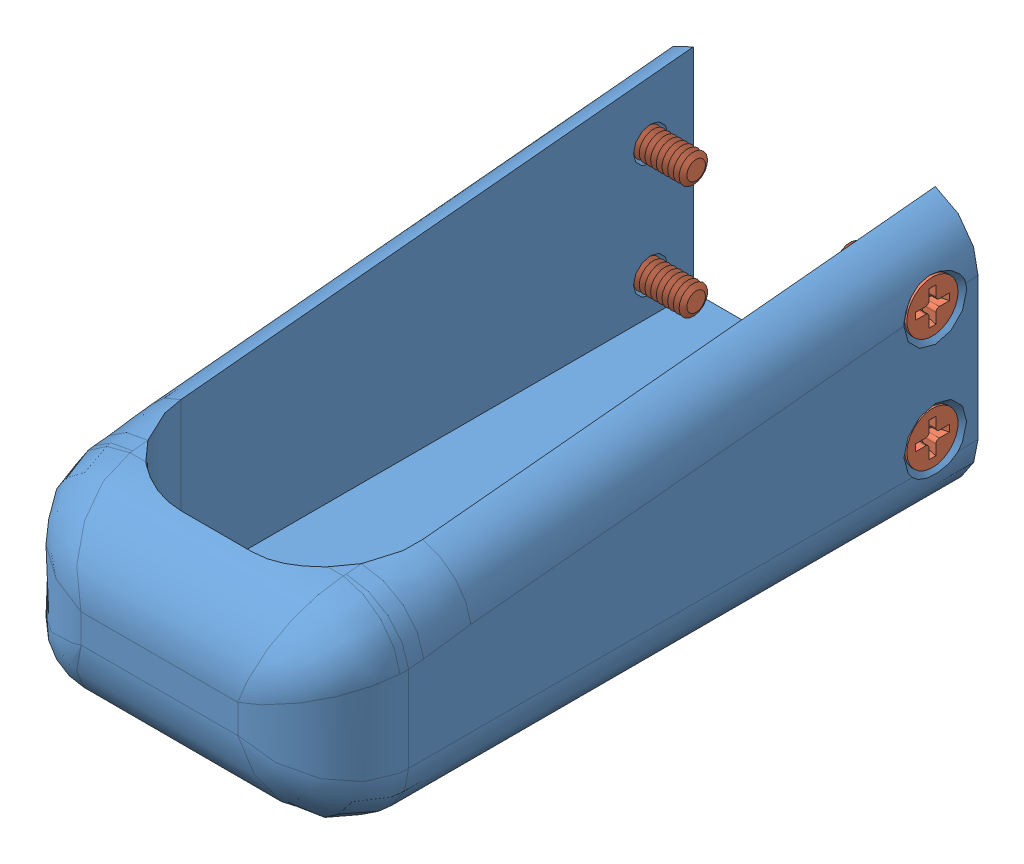
SolidWorks assembly B2586, configuration Default. Lengths in mm.
Overall size (23.31 17.9 46).
5 component instances, 2 part files, 9 mates.
Components (placement in the parent):
- B0926-1: B0926 [Default] at (0 0 -46) x (-1 0 0) z (0 1 0) size (23.31 46 17.9)
- B1090-1: B1090 [M2-.4x6] at (10.3 13.5 -43) x (-1 0 0) z (0 0 1) size (6 3.6 3.6)
- B1090-2: B1090 [M2-.4x6] at (10.3 5.5 -43) x (-1 0 0) z (0 -1 0) size (6 3.6 3.6)
- B1090-3: B1090 [M2-.4x6] at (-10.3 5.5 -43) size (6 3.6 3.6)
- B1090-4: B1090 [M2-.4x6] at (-10.3 13.5 -43) x (1 0 0) z (0 -1 0) size (6 3.6 3.6)
Mates (geometry in assembly coordinates):
- Coincident5: coincident anti-aligned: plane of B0926-1; plane of assembly through (5.5 0 -6) normal (0 -1 0)
- Coincident6: coincident aligned: plane of B0926-1 through (-5.5 17.9 0) normal (0 0 1); plane of assembly
- Coincident7: coincident anti-aligned: plane of B0926-1; plane of assembly
- Coincident8: coincident aligned: cone of B0926-1 through (11.5 5.5 -43) axis (-1 0 0); cone of B1090-2 through (10.3 5.5 -43) axis (-1 0 0)
- Coincident9: coincident aligned: cone of B0926-1 through (11.5 13.5 -43) axis (-1 0 0); cone of B1090-1 through (10.3 13.5 -43) axis (-1 0 0)
- Coincident10: coincident aligned: cone of B0926-1 through (-11.5 13.5 -43) axis (1 0 0); cone of B1090-4 through (-10.3 13.5 -43) axis (1 0 0)
- Coincident11: coincident aligned: cone of B0926-1 through (-11.5 5.5 -43) axis (1 0 0); cone of B1090-3 through (-10.3 5.5 -43) axis (1 0 0)
- Coincident12: coincident anti-aligned: plane of B1090-1; plane of B1090-2
- Coincident13: coincident aligned: plane of B1090-3; plane of B1090-4
